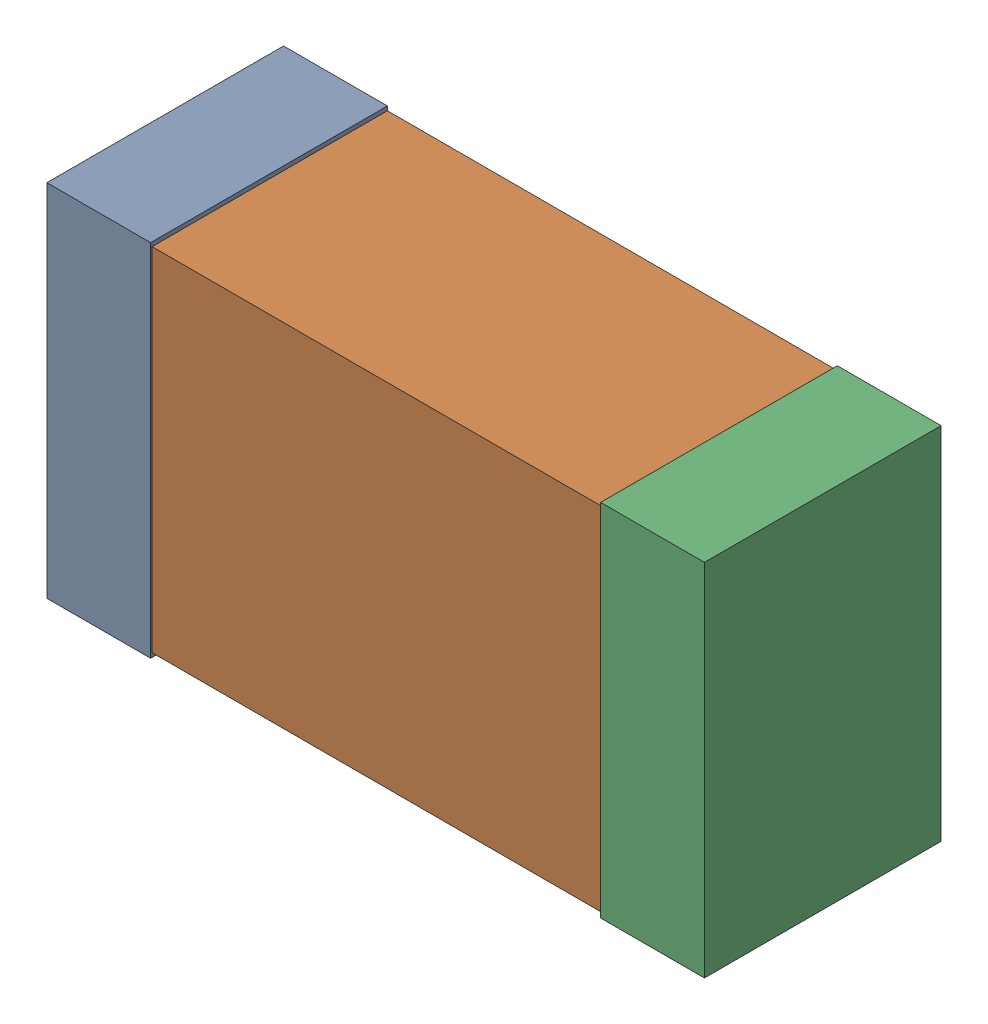
SolidWorks assembly RFBT12Kanaloa_v2.0.0_Power, configuration Default. Lengths in mm.
Overall size (2.38 1.3 0.85).
6 component instances, 2 part files, 0 mates.
Components (placement in the parent):
- 352877648-1: 352877648 [Default] at (50.816 122.682 0) size (0.38 1.3 0.85)
  - Extruded_14-1: Extruded_14 [Default] at origin size (0.38 1.3 0.85)
- 352877392-1: 352877392 [Default] at (51.816 122.682 0) size (2.2 1.27 0.85)
  - Extruded_15-1: Extruded_15 [Default] at origin size (2.2 1.27 0.85)
- 352877648-2: 352877648 [Default] at (52.816 122.682 0) size (0.38 1.3 0.85)
  - Extruded_14-1: Extruded_14 [Default] at origin size (0.38 1.3 0.85)
